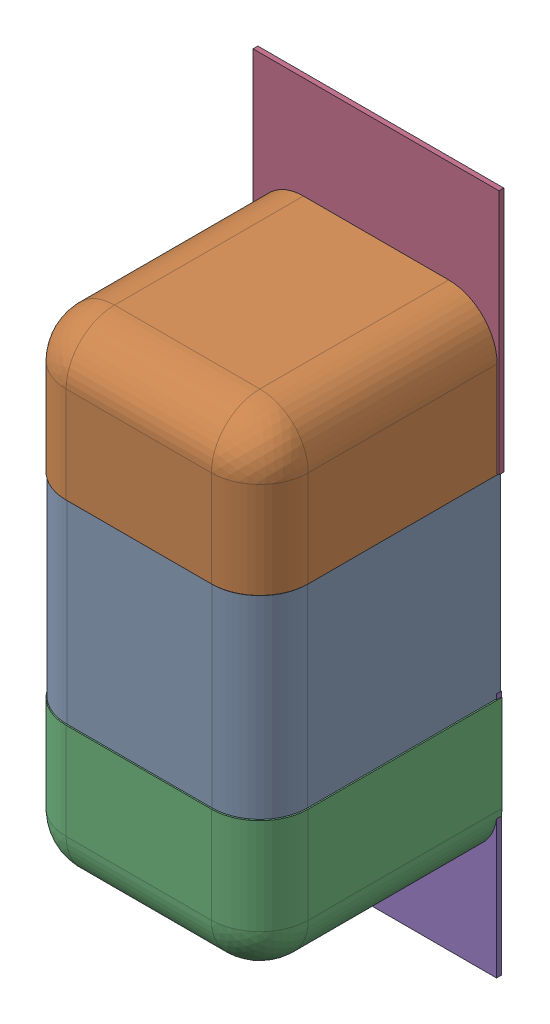
SolidWorks assembly C138, configuration Défaut. Lengths in mm.
Overall size (0.51 1.41 0.5).
8 component instances, 4 part files, 0 mates.
Components (placement in the parent):
- 6501210464-1: 6501210464 [Défaut] at (20.4978 -22.0654 0) x (0 -1 0) z (-1 0 0) size (1 0.5 0.5)
  - Open CASCADE STEP translator 7.5 2.33.1.1-1: Open CASCADE STEP translator 7.5 2.33.1.1 [Défaut] at origin size (0.4 0.5 0.5)
  - Open CASCADE STEP translator 7.5 2.33.1.2-1: Open CASCADE STEP translator 7.5 2.33.1.2 [Défaut] at origin size (0.3 0.5 0.5)
  - Open CASCADE STEP translator 7.5 2.33.1.3-1: Open CASCADE STEP translator 7.5 2.33.1.3 [Défaut] at origin size (0.3 0.5 0.5)
- 6504207776-1: 6504207776 [Défaut] at (20.4978 -21.6081 0) size (0.51 0.51 0.01)
  - Extruded-1: Extruded [Défaut] at origin size (0.51 0.51 0.01)
- 6504207776-2: 6504207776 [Défaut] at (20.4926 -22.5104 0) size (0.51 0.51 0.01)
  - Extruded-1: Extruded [Défaut] at origin size (0.51 0.51 0.01)
